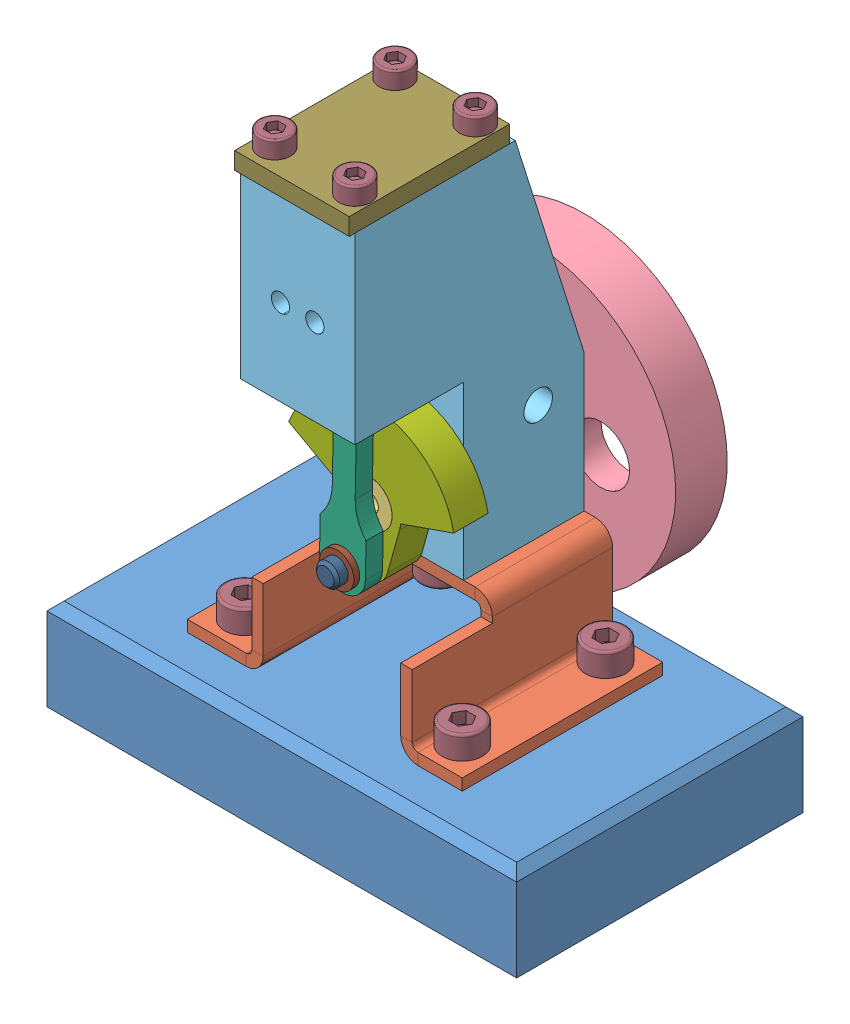
SolidWorks assembly air engien, configuration Default. Lengths in mm.
Overall size (82 102 61).
23 component instances, 13 part files, 54 mates.
Components (placement in the parent):
- base plate-1: base plate [Default] at (4.9996 36.4135 75.3539) size (82 16 50)
- mounting Bracket-1: mounting Bracket [Default] at (28.9996 52.4135 92.8539) size (48 18 35)
- cranck shaft-1: cranck shaft [Default] at (5.2646 80.4135 85.3539) x (0.99644 -0.08431 0) z (0 0 1) size (8 8 46)
- fly wheel-1: fly wheel [Default] at (5.2646 80.4135 47.8539) x (0.99644 -0.08431 0) z (0 0 1) size (50 50 10)
- motor block-1: motor block [Default] at (5.2646 100.4135 78.8539) x (0 0 -1) z (1 0 0) size (40 62 20)
- connecting rod-1: connecting rod [Default] at (4.9273 89.9387 87.8539) x (0.019271 0.999814 0) z (-0.999814 0.019271 0) size (42 3 8)
- cranck-1: cranck [Default] at (5.2646 80.4135 82.3539) x (0.99644 -0.08431 0) z (0 0 -1) size (28.91 27 6.5)
- piston-1: piston [Default] at (5.2646 114.2896 87.8539) size (14 15 14)
- piston pin-1: piston pin [Default] at (5.2646 107.4355 87.8539) size (3 3 13.5)
- cranck pin-1: cranck pin [Default] at (4.5901 72.442 79.3539) x (-0.733213 0.679999 0) z (0 0 1) size (4 4 13)
- washer-1: washer [Default] at (4.5901 72.442 89.3539) x (-0.223046 -0.974808 0) z (0 0 1) size (6 6 1)
- washer-2: washer [Default] at (4.5901 72.442 85.3539) x (-0.328683 -0.94444 0) z (0 0 1) size (6 6 1)
- cylinder head-1: cylinder head [Default] at (5.2646 132.4135 84.8539) x (0 0 1) z (-1 0 0) size (28 3 20)
- socket head cap screw_din-1: socket head cap screw_din [DIN 912 M4 x 8 --- 8N] at (-14.0004 58.4135 62.8539) x (0 -1 0) z (0 0 1) size (12 7 7)
- socket head cap screw_din-2: socket head cap screw_din [DIN 912 M4 x 8 --- 8N] at (-14.0004 58.4135 87.8539) x (0 -1 0) z (0 0 1) size (12 7 7)
- socket head cap screw_din-4: socket head cap screw_din [DIN 912 M4 x 8 --- 8N] at (23.9996 58.4135 62.8539) x (0 -1 0) z (0 0 1) size (12 7 7)
- socket head cap screw_din-5: socket head cap screw_din [DIN 912 M4 x 8 --- 8N] at (23.9996 58.4135 87.8539) x (0 -1 0) z (0 0 1) size (12 7 7)
- socket head cap screw_din-6: socket head cap screw_din [DIN 912 M4 x 8 --- 8N] at (6.2579 64.4135 65.8539) x (0 1 0) z (0 0 1) size (12 7 7)
- socket head cap screw_din-7: socket head cap screw_din [DIN 912 M4 x 8 --- 8N] at (6.2579 64.4135 73.8539) x (0 1 0) z (0 0 1) size (12 7 7)
- socket head cap screw_din-9: socket head cap screw_din [DIN 912 M3 x 12 --- 12N] at (-1.7354 138.4135 73.8539) x (0 -1 0) z (0 0 1) size (15 5.5 5.5)
- socket head cap screw_din-10: socket head cap screw_din [DIN 912 M3 x 12 --- 12N] at (12.2646 138.4135 94.8539) x (0 -1 0) z (0 0 1) size (15 5.5 5.5)
- socket head cap screw_din-12: socket head cap screw_din [DIN 912 M3 x 12 --- 12N] at (-1.7354 138.4135 94.8539) x (0 -1 0) z (0 0 1) size (15 5.5 5.5)
- socket head cap screw_din-13: socket head cap screw_din [DIN 912 M3 x 12 --- 12N] at (12.2646 138.4135 73.8539) x (0 -1 0) z (0 0 1) size (15 5.5 5.5)
Mates (geometry in assembly coordinates):
- Concentric1: concentric aligned: cylinder of base plate-1 through (23.9996 52.4135 87.8539) axis (0 1 0) radius 1.65; cylinder of mounting Bracket-1 through (23.9996 70.4135 87.8539) axis (0 1 0) radius 2
- Concentric2: concentric aligned: cylinder of base plate-1 through (23.9996 52.4135 62.8539) axis (0 1 0) radius 1.65; cylinder of mounting Bracket-1 through (23.9996 70.4135 62.8539) axis (0 1 0) radius 2
- Concentric3: concentric aligned: cylinder of base plate-1 through (-14.0004 52.4135 87.8539) axis (0 1 0) radius 1.65; cylinder of mounting Bracket-1 through (-14.0004 70.4135 87.8539) axis (0 1 0) radius 2
- Concentric4: concentric aligned: cylinder of base plate-1 through (-14.0004 52.4135 62.8539) axis (0 1 0) radius 1.65; cylinder of mounting Bracket-1 through (-14.0004 70.4135 62.8539) axis (0 1 0) radius 2
- Coincident1: coincident anti-aligned: plane of base plate-1 through (4.9996 52.4135 75.3539) normal (0 1 0); plane of mounting Bracket-1 through (-5.7421 52.4135 57.8539) normal (0 -1 0)
- Concentric5: concentric anti-aligned: cylinder of mounting Bracket-1 through (6.2579 70.4135 73.8539) axis (0 1 0) radius 2; cylinder of motor block-1 through (6.2579 70.4135 73.8539) axis (0 -1 0) radius 1.65
- Concentric6: concentric anti-aligned: cylinder of mounting Bracket-1 through (6.2579 70.4135 65.8539) axis (0 1 0) radius 2; cylinder of motor block-1 through (6.2579 70.4135 65.8539) axis (0 -1 0) radius 1.65
- Coincident2: coincident anti-aligned: plane of mounting Bracket-1 through (18.2579 70.4135 57.8539) normal (0 1 0); plane of motor block-1 through (15.2646 70.4135 57.8539) normal (0 -1 0)
- Concentric7: concentric anti-aligned: cylinder of cranck shaft-1 through (5.2646 80.4135 51.3539) axis (0 0 1) radius 4; cylinder of motor block-1 through (5.2646 80.4135 97.8539) axis (0 0 -1) radius 4
- Concentric8: concentric anti-aligned: cylinder of cranck shaft-1 through (5.2646 80.4135 51.3539) axis (0 0 1) radius 4; cylinder of fly wheel-1 through (5.2646 80.4135 56.8539) axis (0 0 -1) radius 4
- Coincident3: coincident anti-aligned: plane of fly wheel-1 through (5.2646 80.4135 57.8539) normal (0 0 1); plane of motor block-1 through (15.2646 94.4135 57.8539) normal (0 0 -1)
- Coincident4: coincident aligned: plane of cranck shaft-1 through (5.2646 80.4135 85.3539) normal (0.08431 0.99644 0); plane of fly wheel-1 through (5.2646 80.4135 47.8539) normal (0.08431 0.99644 0)
- Coincident5: coincident aligned: plane of piston-1 through (5.2646 114.2896 87.8539) normal (0 0 1); plane of piston pin-1 through (5.2646 107.4355 87.8539) normal (0 0 1)
- Concentric9: concentric anti-aligned: cylinder of piston-1 through (5.2646 107.4355 80.8539) axis (0 0 1) radius 1.5; cylinder of piston pin-1 through (5.2646 107.4355 94.6039) axis (0 0 -1) radius 1.5
- Concentric10: concentric anti-aligned: cylinder of connecting rod-1 through (5.2646 107.4355 86.3539) axis (0 0 1) radius 1.5; cylinder of piston pin-1 through (5.2646 107.4355 94.6039) axis (0 0 -1) radius 1.5
- Coincident6: coincident anti-aligned: plane of connecting rod-1 through (4.9273 89.9387 87.8539) normal (0 0 -1); plane of piston pin-1 through (5.2646 107.4355 87.8539) normal (0 0 1)
- Concentric11: concentric aligned: cylinder of motor block-1 through (5.2646 70.4135 87.8539) axis (0 1 0) radius 7; cylinder of piston-1 through (5.2646 115.4355 87.8539) axis (0 1 0) radius 7
- Concentric12: concentric aligned: cylinder of cranck shaft-1 through (5.2646 80.4135 51.3539) axis (0 0 1) radius 4; cylinder of cranck-1 through (5.2646 80.4135 78.8539) axis (0 0 1) radius 4
- Concentric13: concentric aligned: cylinder of connecting rod-1 through (4.5901 72.442 86.3539) axis (0 0 1) radius 2; cylinder of cranck-1 through (4.5901 72.442 79.3539) axis (0 0 1) radius 2
- Concentric16: concentric anti-aligned: cylinder of cranck-1 through (4.5901 72.442 79.3539) axis (0 0 1) radius 2; cylinder of cranck pin-1 through (4.5901 72.442 92.3539) axis (0 0 -1) radius 2
- Coincident7: coincident aligned: plane of cranck-1 through (5.2646 80.4135 79.3539) normal (0 0 -1); plane of cranck pin-1 through (4.5901 72.442 79.3539) normal (0 0 -1)
- Concentric17: concentric anti-aligned: cylinder of cranck pin-1 through (4.5901 72.442 88.3539) axis (0 0 1) radius 1.9; cylinder of washer-1 through (4.5901 72.442 90.3539) axis (0 0 -1) radius 1.9
- Coincident8: coincident anti-aligned: plane of connecting rod-1 through (4.9273 89.9387 89.3539) normal (0 0 1); plane of washer-1 through (4.5901 72.442 89.3539) normal (0 0 -1)
- Concentric18: concentric aligned: cylinder of cranck pin-1 through (4.5901 72.442 92.3539) axis (0 0 -1) radius 2; cylinder of washer-2 through (4.5901 72.442 86.3539) axis (0 0 -1) radius 1.9
- Coincident9: coincident anti-aligned: plane of cranck-1 through (5.2646 80.4135 85.3539) normal (0 0 1); plane of washer-2 through (4.5901 72.442 85.3539) normal (0 0 -1)
- Coincident10: coincident aligned: plane of cranck shaft-1 through (5.2646 80.4135 85.3539) normal (0 0 1); plane of cranck-1 through (5.2646 80.4135 85.3539) normal (0 0 1)
- Coincident11: coincident aligned: plane of cranck shaft-1 through (5.2646 80.4135 85.3539) normal (0 0 1); plane of cranck-1 through (5.2646 80.4135 85.3539) normal (0 0 1)
- Coincident12: coincident anti-aligned: plane of connecting rod-1 through (4.9273 89.9387 86.3539) normal (0 0 -1); plane of washer-2 through (4.5901 72.442 86.3539) normal (0 0 1)
- Coincident13: coincident aligned: plane of cranck shaft-1 through (5.2646 80.4135 85.3539) normal (0.99644 -0.08431 0); plane of cranck-1 through (5.2646 80.4135 82.3539) normal (0.99644 -0.08431 0)
- Concentric20: concentric aligned: cylinder of motor block-1 through (12.2646 132.4135 73.8539) axis (0 1 0) radius 1.25; cylinder of cylinder head-1 through (12.2646 135.4135 73.8539) axis (0 1 0) radius 1.25
- Concentric21: concentric aligned: cylinder of motor block-1 through (-1.7354 132.4135 94.8539) axis (0 1 0) radius 1.25; cylinder of cylinder head-1 through (-1.7354 135.4135 94.8539) axis (0 1 0) radius 1.25
- Concentric22: concentric aligned: cylinder of motor block-1 through (-1.7354 132.4135 73.8539) axis (0 1 0) radius 1.25; cylinder of cylinder head-1 through (-1.7354 135.4135 73.8539) axis (0 1 0) radius 1.25
- Concentric23: concentric aligned: cylinder of motor block-1 through (-1.7354 132.4135 94.8539) axis (0 1 0) radius 1.25; cylinder of cylinder head-1 through (-1.7354 135.4135 94.8539) axis (0 1 0) radius 1.25
- Coincident14: coincident anti-aligned: plane of motor block-1 through (15.2646 132.4135 97.8539) normal (0 1 0); plane of cylinder head-1 through (5.2646 132.4135 84.8539) normal (0 -1 0)
- Concentric24: concentric aligned: cylinder of mounting Bracket-1 through (-14.0004 70.4135 62.8539) axis (0 1 0) radius 2; cylinder of socket head cap screw_din-1 through (-14.0004 90.1635 62.8539) axis (0 1 0) radius 3.5
- Coincident15: coincident anti-aligned: plane of mounting Bracket-1 through (-5.7421 54.4135 57.8539) normal (0 1 0); plane of socket head cap screw_din-1 through (-10.5004 54.4135 62.8539) normal (0 -1 0)
- Concentric25: concentric aligned: cylinder of mounting Bracket-1 through (-14.0004 70.4135 87.8539) axis (0 1 0) radius 2; cylinder of socket head cap screw_din-2 through (-14.0004 90.1635 87.8539) axis (0 1 0) radius 3.5
- Coincident16: coincident anti-aligned: plane of mounting Bracket-1 through (-5.7421 54.4135 57.8539) normal (0 1 0); plane of socket head cap screw_din-2 through (-10.5004 54.4135 87.8539) normal (0 -1 0)
- Concentric27: concentric aligned: cylinder of mounting Bracket-1 through (23.9996 70.4135 62.8539) axis (0 1 0) radius 2; cylinder of socket head cap screw_din-4 through (23.9996 90.1635 62.8539) axis (0 1 0) radius 3.5
- Coincident17: coincident anti-aligned: plane of mounting Bracket-1 through (28.9996 54.4135 57.8539) normal (0 1 0); plane of socket head cap screw_din-4 through (27.4996 54.4135 62.8539) normal (0 -1 0)
- Concentric28: concentric aligned: cylinder of mounting Bracket-1 through (23.9996 70.4135 87.8539) axis (0 1 0) radius 2; cylinder of socket head cap screw_din-5 through (23.9996 90.1635 87.8539) axis (0 1 0) radius 3.5
- Coincident18: coincident anti-aligned: plane of mounting Bracket-1 through (28.9996 54.4135 57.8539) normal (0 1 0); plane of socket head cap screw_din-5 through (27.4996 54.4135 87.8539) normal (0 -1 0)
- Concentric29: concentric anti-aligned: cylinder of mounting Bracket-1 through (6.2579 70.4135 65.8539) axis (0 1 0) radius 2; cylinder of socket head cap screw_din-6 through (6.2579 32.6635 65.8539) axis (0 -1 0) radius 3.5
- Coincident19: coincident anti-aligned: plane of mounting Bracket-1 through (18.2579 68.4135 57.8539) normal (0 -1 0); plane of socket head cap screw_din-6 through (2.7579 68.4135 65.8539) normal (0 1 0)
- Concentric30: concentric anti-aligned: cylinder of mounting Bracket-1 through (6.2579 70.4135 73.8539) axis (0 1 0) radius 2; cylinder of socket head cap screw_din-7 through (6.2579 32.6635 73.8539) axis (0 -1 0) radius 3.5
- Coincident20: coincident anti-aligned: plane of mounting Bracket-1 through (18.2579 68.4135 57.8539) normal (0 -1 0); plane of socket head cap screw_din-7 through (2.7579 68.4135 73.8539) normal (0 1 0)
- Concentric31: concentric aligned: cylinder of cylinder head-1 through (-1.7354 135.4135 73.8539) axis (0 1 0) radius 1.25; cylinder of socket head cap screw_din-9 through (-1.7354 170.1635 73.8539) axis (0 1 0) radius 2.75
- Coincident21: coincident anti-aligned: plane of cylinder head-1 through (5.2646 135.4135 84.8539) normal (0 1 0); plane of socket head cap screw_din-9 through (1.0146 135.4135 73.8539) normal (0 -1 0)
- Concentric32: concentric aligned: cylinder of cylinder head-1 through (12.2646 135.4135 94.8539) axis (0 1 0) radius 1.25; cylinder of socket head cap screw_din-10 through (12.2646 170.1635 94.8539) axis (0 1 0) radius 2.75
- Coincident22: coincident anti-aligned: plane of cylinder head-1 through (5.2646 135.4135 84.8539) normal (0 1 0); plane of socket head cap screw_din-10 through (15.0146 135.4135 94.8539) normal (0 -1 0)
- Concentric33: concentric aligned: cylinder of cylinder head-1 through (-1.7354 135.4135 94.8539) axis (0 1 0) radius 1.25; cylinder of socket head cap screw_din-12 through (-1.7354 170.1635 94.8539) axis (0 1 0) radius 2.75
- Coincident24: coincident anti-aligned: plane of cylinder head-1 through (5.2646 135.4135 84.8539) normal (0 1 0); plane of socket head cap screw_din-12 through (1.0146 135.4135 94.8539) normal (0 -1 0)
- Concentric34: concentric aligned: cylinder of cylinder head-1 through (12.2646 135.4135 73.8539) axis (0 1 0) radius 1.25; cylinder of socket head cap screw_din-13 through (12.2646 170.1635 73.8539) axis (0 1 0) radius 2.75
- Coincident25: coincident anti-aligned: plane of cylinder head-1 through (5.2646 135.4135 84.8539) normal (0 1 0); plane of socket head cap screw_din-13 through (15.0146 135.4135 73.8539) normal (0 -1 0)
